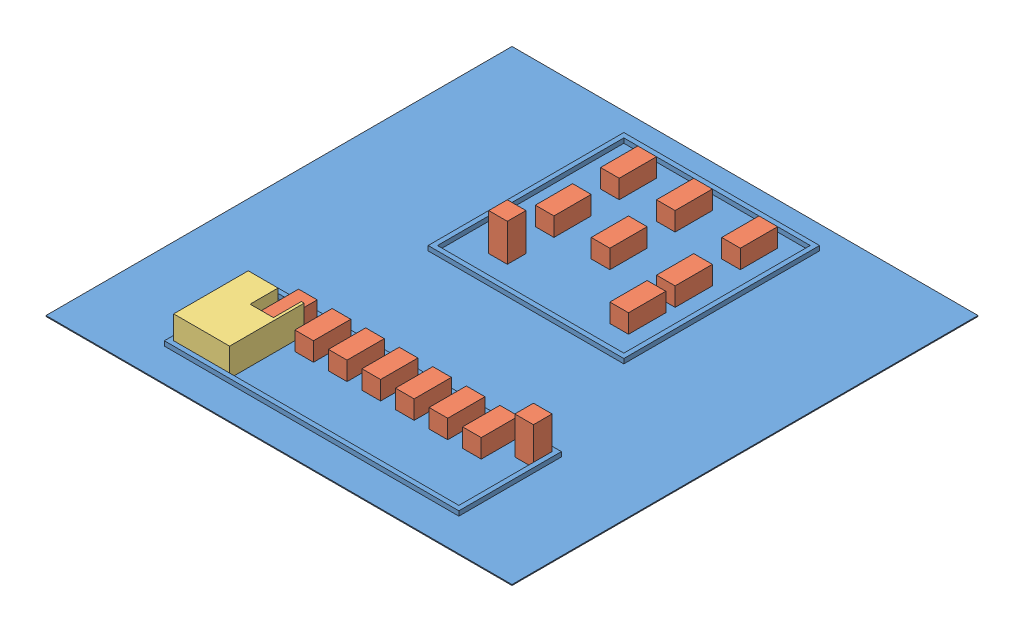
SolidWorks assembly plan, configuration Default. Lengths in mm.
Overall size (5000 410 5000).
18 component instances, 3 part files, 52 mates.
Components (placement in the parent):
- arena-1: arena [Default] at (-664.193 2010.695 1740.3372) size (5000 60 5000)
- boxes-1: boxes [Default] at (1135.807 2020.695 3590.3372) size (200 400 200)
- boxes-2: boxes [Default] at (1735.807 2220.695 2190.3372) x (1 0 0) z (0 -1 0) size (200 400 200)
- boxes-3: boxes [Default] at (1735.807 2220.695 2890.3372) x (1 0 0) z (0 -1 0) size (200 400 200)
- boxes-4: boxes [Default] at (2435.807 2220.695 3390.3372) x (1 0 0) z (0 -1 0) size (200 400 200)
- boxes-5: boxes [Default] at (1135.807 2220.695 2890.3372) x (1 0 0) z (0 -1 0) size (200 400 200)
- boxes-6: boxes [Default] at (1135.807 2220.695 2190.3372) x (1 0 0) z (0 -1 0) size (200 400 200)
- boxes-7: boxes [Default] at (2435.807 2220.695 2190.3372) x (1 0 0) z (0 -1 0) size (200 400 200)
- boxes-8: boxes [Default] at (1005.807 2220.695 5340.3372) x (1 0 0) z (0 -1 0) size (200 400 200)
- boxes-9: boxes [Default] at (1365.807 2220.695 5340.3372) x (1 0 0) z (0 -1 0) size (200 400 200)
- boxes-10: boxes [Default] at (2435.807 2220.695 2890.3372) x (1 0 0) z (0 -1 0) size (200 400 200)
- boxes-11: boxes [Default] at (645.807 2220.695 5340.3372) x (1 0 0) z (0 -1 0) size (200 400 200)
- boxes-12: boxes [Default] at (1725.807 2220.695 5340.3372) x (1 0 0) z (0 -1 0) size (200 400 200)
- boxes-13: boxes [Default] at (2805.807 2220.695 5340.3372) x (1 0 0) z (0 -1 0) size (200 400 200)
- boxes-14: boxes [Default] at (2445.807 2220.695 5340.3372) x (1 0 0) z (0 -1 0) size (200 400 200)
- boxes-15: boxes [Default] at (2085.807 2220.695 5340.3372) x (1 0 0) z (0 -1 0) size (200 400 200)
- boxes-17: boxes [Default] at (3165.807 2020.695 5340.3372) size (200 400 200)
- robot-1: robot [Default] at (305.807 2020.695 5540.3372) size (600 300 800)
Mates (geometry in assembly coordinates):
- Coincident2: coincident anti-aligned: plane of arena-1 through (-664.193 2020.695 1740.3372) normal (0 1 0); plane of boxes-1 through (1135.807 2020.695 3590.3372) normal (0 -1 0)
- Coincident3: coincident anti-aligned: plane of arena-1 through (-664.193 2020.695 1740.3372) normal (0 1 0); plane of boxes-2 through (1735.807 2020.695 2590.3372) normal (0 -1 0)
- Parallel1: parallel aligned: plane of arena-1 through (785.807 2070.695 1990.3372) normal (-1 0 0); plane of boxes-2 through (1735.807 2220.695 2590.3372) normal (-1 0 0)
- Parallel2: parallel aligned: plane of arena-1 through (785.807 2070.695 1990.3372) normal (-1 0 0); plane of boxes-1 through (1135.807 2420.695 3590.3372) normal (-1 0 0)
- Coincident6: coincident anti-aligned: plane of arena-1 through (-664.193 2020.695 1740.3372) normal (0 1 0); plane of boxes-9 through (1365.807 2020.695 5740.3372) normal (0 -1 0)
- Coincident7: coincident anti-aligned: plane of arena-1 through (-664.193 2020.695 1740.3372) normal (0 1 0); plane of boxes-11 through (645.807 2020.695 5740.3372) normal (0 -1 0)
- Coincident8: coincident anti-aligned: plane of arena-1 through (-664.193 2020.695 1740.3372) normal (0 1 0); plane of boxes-12 through (1725.807 2020.695 5740.3372) normal (0 -1 0)
- Coincident9: coincident anti-aligned: plane of arena-1 through (-664.193 2020.695 1740.3372) normal (0 1 0); plane of boxes-8 through (1005.807 2020.695 5740.3372) normal (0 -1 0)
- Coincident10: coincident anti-aligned: plane of arena-1 through (-664.193 2020.695 1740.3372) normal (0 1 0); plane of boxes-7 through (2468.5074 2020.695 2590.3372) normal (0 -1 0)
- Coincident11: coincident anti-aligned: plane of arena-1 through (-664.193 2020.695 1740.3372) normal (0 1 0); plane of boxes-6 through (1135.807 2020.695 2590.3372) normal (0 -1 0)
- Coincident12: coincident anti-aligned: plane of arena-1 through (-664.193 2020.695 1740.3372) normal (0 1 0); plane of boxes-5 through (1135.807 2020.695 3290.3372) normal (0 -1 0)
- Coincident13: coincident anti-aligned: plane of arena-1 through (-664.193 2020.695 1740.3372) normal (0 1 0); plane of boxes-4 through (2468.5074 2020.695 3790.3372) normal (0 -1 0)
- Coincident14: coincident anti-aligned: plane of arena-1 through (-664.193 2020.695 1740.3372) normal (0 1 0); plane of boxes-3 through (1735.807 2020.695 3290.3372) normal (0 -1 0)
- Coincident16: coincident anti-aligned: plane of arena-1 through (-664.193 2020.695 1740.3372) normal (0 1 0); plane of boxes-10 through (2468.5074 2020.695 3290.3372) normal (0 -1 0)
- Parallel3: parallel aligned: plane of arena-1 through (785.807 2070.695 1990.3372) normal (-1 0 0); plane of boxes-3 through (1735.807 2220.695 3290.3372) normal (-1 0 0)
- Coincident18: coincident anti-aligned: plane of arena-1 through (-664.193 2020.695 1740.3372) normal (0 1 0); plane of boxes-17 through (3165.807 2020.695 5340.3372) normal (0 -1 0)
- Coincident19: coincident anti-aligned: plane of arena-1 through (-664.193 2020.695 1740.3372) normal (0 1 0); plane of boxes-13 through (2805.807 2020.695 5740.3372) normal (0 -1 0)
- Coincident20: coincident anti-aligned: plane of arena-1 through (-664.193 2020.695 1740.3372) normal (0 1 0); plane of boxes-14 through (2445.807 2020.695 5740.3372) normal (0 -1 0)
- Coincident21: coincident anti-aligned: plane of arena-1 through (-664.193 2020.695 1740.3372) normal (0 1 0); plane of boxes-15 through (2085.807 2020.695 5740.3372) normal (0 -1 0)
- Coincident22: coincident anti-aligned: plane of arena-1 through (-664.193 2020.695 1740.3372) normal (0 1 0); plane of robot-1 through (305.807 2020.695 5540.3372) normal (0 -1 0)
- Coincident23: coincident anti-aligned: plane of arena-1 through (305.807 2070.695 5340.3372) normal (0 0 1); plane of boxes-11 through (645.807 2220.695 5340.3372) normal (0 0 -1)
- Coincident24: coincident anti-aligned: plane of arena-1 through (305.807 2070.695 5340.3372) normal (0 0 1); plane of boxes-8 through (1005.807 2220.695 5340.3372) normal (0 0 -1)
- Coincident25: coincident anti-aligned: plane of arena-1 through (305.807 2070.695 5340.3372) normal (0 0 1); plane of boxes-9 through (1365.807 2220.695 5340.3372) normal (0 0 -1)
- Coincident26: coincident anti-aligned: plane of arena-1 through (305.807 2070.695 5340.3372) normal (0 0 1); plane of boxes-12 through (1725.807 2220.695 5340.3372) normal (0 0 -1)
- Coincident27: coincident anti-aligned: plane of arena-1 through (305.807 2070.695 5340.3372) normal (0 0 1); plane of boxes-15 through (2085.807 2220.695 5340.3372) normal (0 0 -1)
- Coincident28: coincident anti-aligned: plane of arena-1 through (305.807 2070.695 5340.3372) normal (0 0 1); plane of boxes-14 through (2445.807 2220.695 5340.3372) normal (0 0 -1)
- Coincident29: coincident anti-aligned: plane of arena-1 through (305.807 2070.695 5340.3372) normal (0 0 1); plane of boxes-13 through (2805.807 2220.695 5340.3372) normal (0 0 -1)
- Coincident30: coincident anti-aligned: plane of arena-1 through (305.807 2070.695 5340.3372) normal (0 0 1); plane of boxes-17 through (3165.807 2420.695 5340.3372) normal (0 0 -1)
- Coincident31: coincident anti-aligned: plane of arena-1 through (3365.807 2070.695 5340.3372) normal (-1 0 0); plane of boxes-17 through (3365.807 2420.695 5340.3372) normal (1 0 0)
- Distance1: distance = 160 mm anti-aligned: plane of boxes-17 through (3165.807 2420.695 5340.3372) normal (-1 0 0); plane of boxes-13 through (3005.807 2220.695 5740.3372) normal (1 0 0)
- Distance2: distance = 160 mm anti-aligned: plane of boxes-13 through (2805.807 2220.695 5740.3372) normal (-1 0 0); plane of boxes-14 through (2645.807 2220.695 5740.3372) normal (1 0 0)
- Distance3: distance = 160 mm anti-aligned: plane of boxes-14 through (2445.807 2220.695 5740.3372) normal (-1 0 0); plane of boxes-15 through (2285.807 2220.695 5740.3372) normal (1 0 0)
- Distance4: distance = 160 mm anti-aligned: plane of boxes-15 through (2085.807 2220.695 5740.3372) normal (-1 0 0); plane of boxes-12 through (1925.807 2220.695 5740.3372) normal (1 0 0)
- Distance5: distance = 160 mm anti-aligned: plane of boxes-12 through (1725.807 2220.695 5740.3372) normal (-1 0 0); plane of boxes-9 through (1565.807 2220.695 5740.3372) normal (1 0 0)
- Distance6: distance = 160 mm anti-aligned: plane of boxes-9 through (1365.807 2220.695 5740.3372) normal (-1 0 0); plane of boxes-8 through (1205.807 2220.695 5740.3372) normal (1 0 0)
- Distance7: distance = 160 mm anti-aligned: plane of boxes-8 through (1005.807 2220.695 5740.3372) normal (-1 0 0); plane of boxes-11 through (845.807 2220.695 5740.3372) normal (1 0 0)
- Distance8: distance = 150 mm anti-aligned: plane of boxes-6 through (1135.807 2220.695 2190.3372) normal (0 0 -1); plane of arena-1 through (835.807 2070.695 2040.3372) normal (0 0 1)
- Distance9: distance = 300 mm anti-aligned: plane of boxes-5 through (1135.807 2220.695 2890.3372) normal (0 0 -1); plane of boxes-6 through (1135.807 2220.695 2590.3372) normal (0 0 1)
- Distance10: distance = 300 mm anti-aligned: plane of boxes-1 through (1135.807 2420.695 3590.3372) normal (0 0 -1); plane of boxes-5 through (1135.807 2220.695 3290.3372) normal (0 0 1)
- Coincident35: coincident aligned: plane of boxes-5 through (1135.807 2220.695 3290.3372) normal (-1 0 0); plane of boxes-6 through (1135.807 2220.695 2590.3372) normal (-1 0 0)
- Coincident36: coincident aligned: plane of boxes-1 through (1135.807 2420.695 3590.3372) normal (-1 0 0); plane of boxes-5 through (1135.807 2220.695 3290.3372) normal (-1 0 0)
- Distance11: distance = 300 mm anti-aligned: plane of boxes-6 through (1135.807 2220.695 2590.3372) normal (-1 0 0); plane of arena-1 through (835.807 2070.695 2040.3372) normal (1 0 0)
- Coincident38: coincident aligned: plane of boxes-2 through (1735.807 2220.695 2190.3372) normal (0 0 -1); plane of boxes-6 through (1135.807 2220.695 2190.3372) normal (0 0 -1)
- Coincident39: coincident aligned: plane of boxes-3 through (1735.807 2220.695 2890.3372) normal (0 0 -1); plane of boxes-5 through (1135.807 2220.695 2890.3372) normal (0 0 -1)
- Coincident40: coincident aligned: plane of boxes-2 through (1735.807 2220.695 2590.3372) normal (-1 0 0); plane of boxes-3 through (1735.807 2220.695 3290.3372) normal (-1 0 0)
- Distance12: distance = 400 mm anti-aligned: plane of boxes-2 through (1735.807 2220.695 2590.3372) normal (-1 0 0); plane of boxes-6 through (1335.807 2220.695 2590.3372) normal (1 0 0)
- Coincident42: coincident aligned: plane of boxes-2 through (1735.807 2220.695 2190.3372) normal (0 0 -1); plane of boxes-7 through (2468.5074 2220.695 2190.3372) normal (0 0 -1)
- Coincident43: coincident aligned: plane of boxes-3 through (1735.807 2220.695 2890.3372) normal (0 0 -1); plane of boxes-10 through (2468.5074 2220.695 2890.3372) normal (0 0 -1)
- Coincident44: coincident aligned: plane of boxes-1 through (1135.807 2420.695 3790.3372) normal (0 0 1); plane of boxes-4 through (2468.5074 2220.695 3790.3372) normal (0 0 1)
- Coincident46: coincident aligned: plane of boxes-7 through (2435.807 2220.695 2590.3372) normal (-1 0 0); plane of boxes-10 through (2435.807 2220.695 3290.3372) normal (-1 0 0)
- Coincident47: coincident aligned: plane of boxes-4 through (2435.807 2220.695 3790.3372) normal (-1 0 0); plane of boxes-10 through (2435.807 2220.695 3290.3372) normal (-1 0 0)
- Distance13: distance = 500 mm anti-aligned: plane of boxes-7 through (2435.807 2220.695 2590.3372) normal (-1 0 0); plane of boxes-2 through (1935.807 2220.695 2590.3372) normal (1 0 0)
